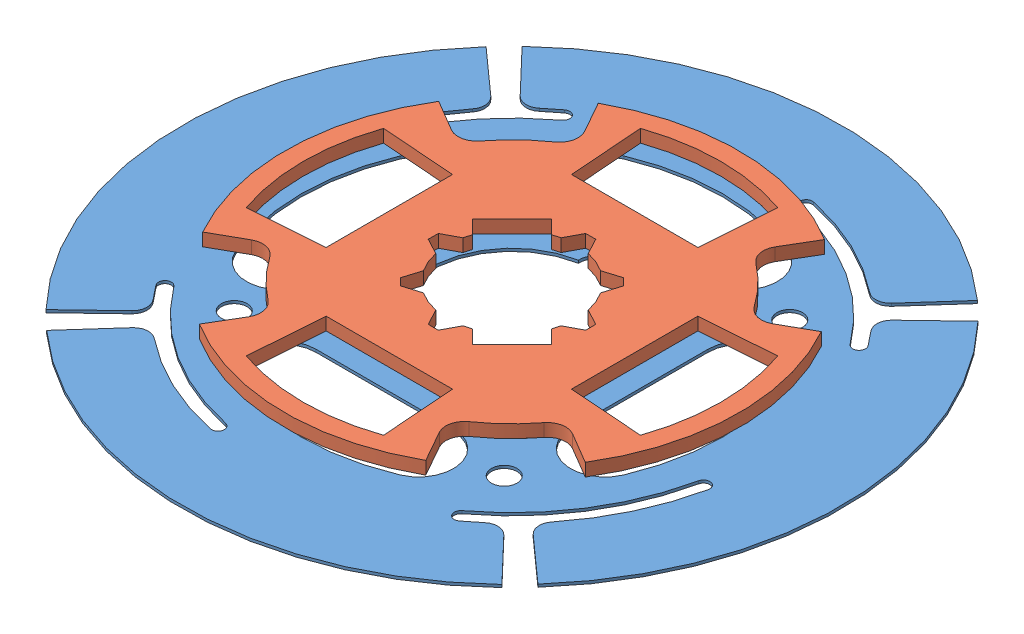
SolidWorks assembly Assem2, configuration Default. Lengths in mm.
Overall size (180 8.7 180).
2 component instances, 2 part files, 3 mates.
Components (placement in the parent):
- 7-2: 7 [Default] at (49.9985 91.1987 149.0949) size (180 0.75 180)
- 6-2: 6 [Default] at (49.9985 98.1463 149.0949) x (1 0 0) z (0 -1 0) size (124 124 3.5)
Mates (geometry in assembly coordinates):
- Concentric11: concentric anti-aligned: cylinder of 7-2 through (49.9985 91.9487 149.0949) axis (0 -1 0) radius 22.5; cylinder of 6-2 through (49.9985 96.3963 149.0949) axis (0 1 0) radius 62
- Parallel3: parallel aligned: plane of 7-2 through (84.7485 91.1987 130.3449) normal (1 0 0); plane of 6-2 through (83.4985 96.3963 149.0949) normal (1 0 0)
- Parallel4: parallel aligned: plane of 7-2 through (84.7485 91.1987 130.3449) normal (1 0 0); plane of 6-2 through (83.4985 96.3963 149.0949) normal (1 0 0)
